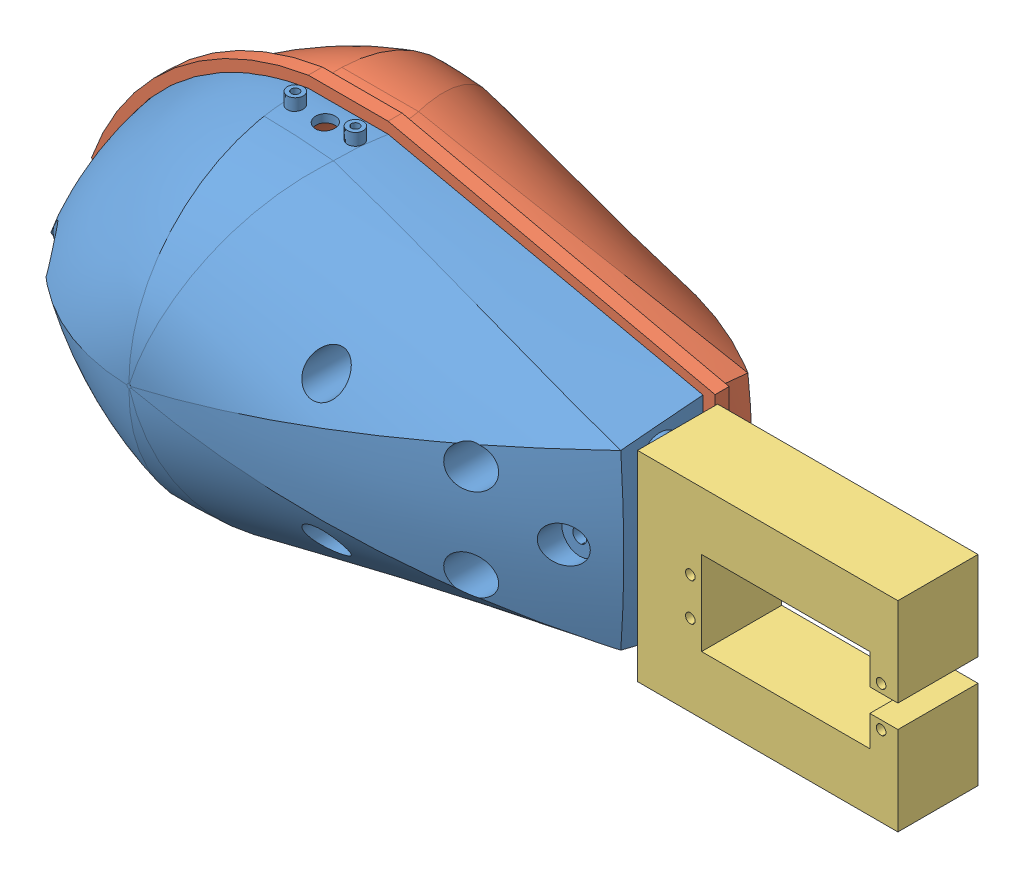
SolidWorks assembly Assem1, configuration Default. Lengths in mm.
Overall size (255.18 90 94.52).
3 component instances, 3 part files, 4 mates.
Components (placement in the parent):
- 下面-1: 下面 [預設] at origin size (169.53 90 49.49)
- 上面-1: 上面 [預設] at (0 0 -2.2867) x (1 0 0) z (0 0 -1) size (189.68 89.69 63.09)
- 後面2-1: 後面2 [預設] at (151.6953 1.7673 0.0811) x (0 -1 0) z (0 0 1) size (50 65 20)
Mates (geometry in assembly coordinates):
- Concentric4: concentric: circle of 下面-1; cylinder of 上面-1 through (138.1989 0 17.7133) axis (0 0 -1) radius 1.5
- Concentric5: concentric: cylinder of 下面-1 through (11.1989 0 45) axis (0 0 -1) radius 1.75; cylinder of 上面-1 through (11.1989 0 17.7133) axis (0 0 -1) radius 1.5
- Concentric6: concentric: cylinder of 下面-1 through (146.5 -17 10) axis (1 0 0) radius 4.5; cylinder of 後面2-1 through (166.6953 -17 10) axis (-1 0 0) radius 7
- Concentric7: concentric: cylinder of 下面-1 through (146.5 17 10) axis (1 0 0) radius 4.5; cylinder of 後面2-1 through (166.6953 17 10) axis (-1 0 0) radius 7
